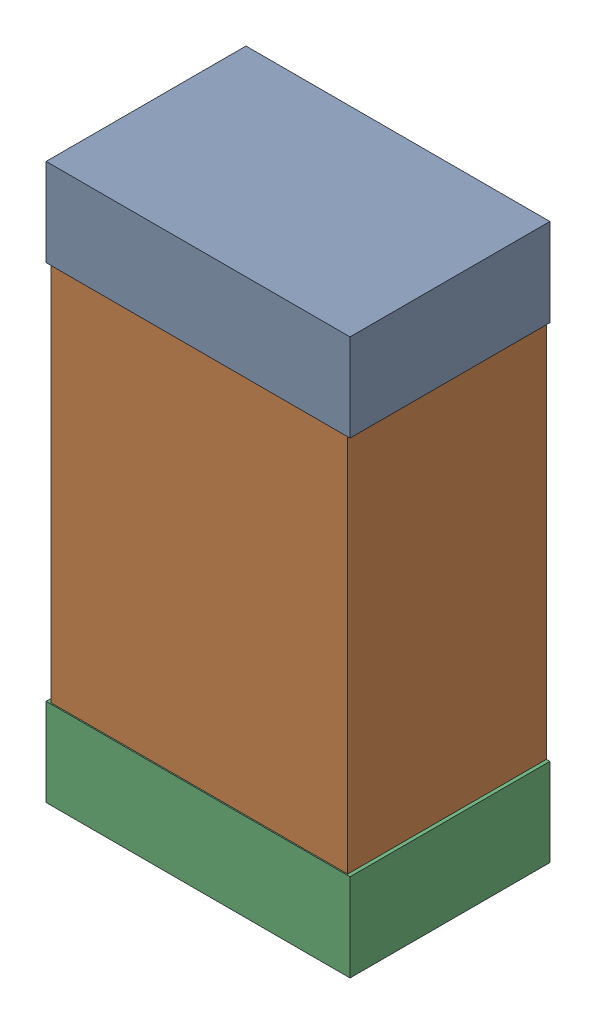
SolidWorks assembly R3_Motor_8Kanaloa_v2.0.0_Loko, configuration Default. Lengths in mm.
Overall size (1.3 2.38 0.85).
6 component instances, 2 part files, 0 mates.
Components (placement in the parent):
- 330415056_1-1: 330415056_1 [Default] at (110.1463 80.2144 0) size (1.3 0.38 0.85)
  - Extruded_29-1: Extruded_29 [Default] at origin size (1.3 0.38 0.85)
- 334787376_1-1: 334787376_1 [Default] at (110.1463 79.2144 0) size (1.27 2.2 0.85)
  - Extruded_30-1: Extruded_30 [Default] at origin size (1.27 2.2 0.85)
- 330415056_1-2: 330415056_1 [Default] at (110.1463 78.2144 0) size (1.3 0.38 0.85)
  - Extruded_29-1: Extruded_29 [Default] at origin size (1.3 0.38 0.85)
